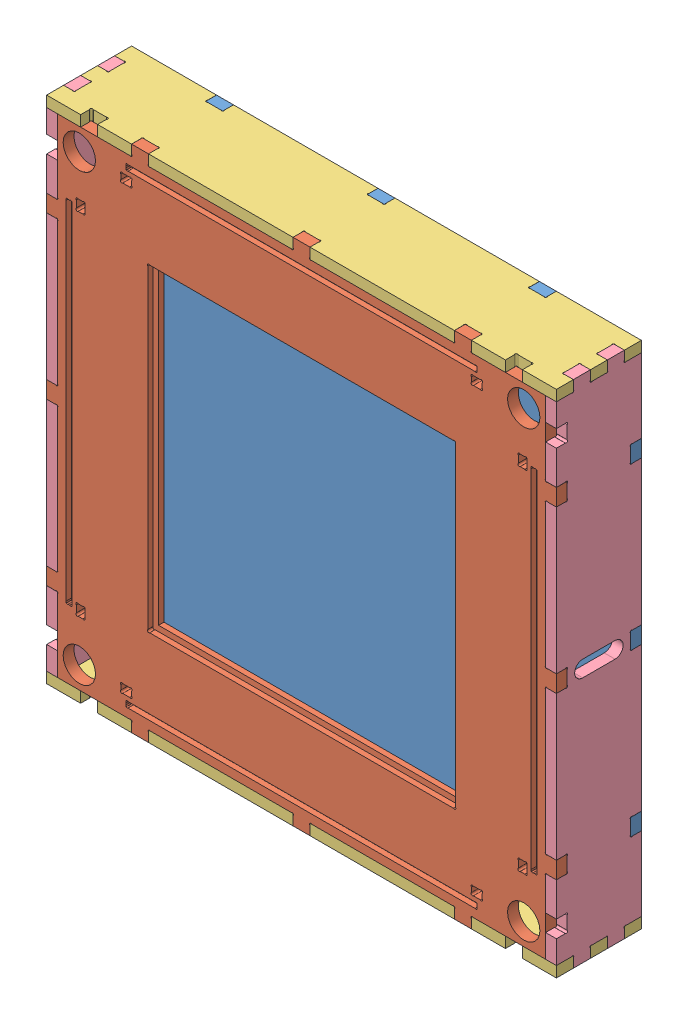
SolidWorks assembly res_assembly, configuration Default. Lengths in mm.
Overall size (300 300 50).
6 component instances, 4 part files, 15 mates.
Components (placement in the parent):
- pvc-025-res03-1: pvc-025-res03 [Default] at (-184.3986 -126.0576 6.3755) size (300 300 6.35)
- pvc-025-res01-1: pvc-025-res01 [Default] at (-184.3986 -126.0576 50.0255) size (300 300 6.35)
- pvc-250-res02-1: pvc-250-res02 [Default] at (102.9014 167.5924 56.3755) x (-1 0 0) z (0 -1 0) size (300 50 6.35)
- pvc-025-res04-1: pvc-025-res04 [a] at (-190.7486 161.2424 56.3755) x (0 -1 0) z (1 0 0) size (300 50 6.35)
- pvc-250-res02-5: pvc-250-res02 [Default] at (102.9014 -126.0576 56.3755) x (-1 0 0) z (0 -1 0) size (300 50 6.35)
- pvc-025-res04-2: pvc-025-res04 [b] at (109.2514 -126.0576 56.3755) x (0 1 0) z (-1 0 0) size (300 50 6.35)
Mates (geometry in assembly coordinates):
- Coincident1: coincident: plane of assembly; plane of assembly; plane of pvc-025-res01-1 through (103.4627 -82.9689 56.3755) normal (0 0 1); plane of pvc-250-res02-1 through (-130.7829 161.2424 56.3755) normal (0 0 1)
- Coincident2: coincident: plane of pvc-025-res01-1 through (-45.7486 167.5924 56.3755) normal (0 1 0); plane of pvc-250-res02-1 through (103.4627 167.5924 16.9368) normal (0 1 0)
- Coincident5: coincident: plane of pvc-025-res03-1 through (103.4627 -82.9689 6.3755) normal (0 0 -1); plane of pvc-250-res02-1 through (49.2171 161.2424 6.3755) normal (0 0 -1)
- Coincident6: coincident: plane of pvc-025-res03-1 through (-45.7486 167.5924 12.7255) normal (0 1 0); plane of pvc-250-res02-1 through (103.4627 167.5924 16.9368) normal (0 1 0)
- Coincident8: coincident: plane of pvc-025-res03-1 through (-184.3986 23.7149 12.7255) normal (-1 0 0); plane of pvc-025-res04-1 through (-184.3986 161.8036 15.8142) normal (1 0 0)
- Coincident9: coincident: plane of pvc-250-res02-1 through (103.4627 167.5924 16.9368) normal (0 1 0); plane of pvc-025-res04-1 through (-184.3986 167.5924 46.3755) normal (0 1 0)
- Coincident10: coincident: plane of pvc-250-res02-1 through (-190.7486 161.2424 56.3755) normal (0 0 1); plane of pvc-025-res04-1 through (-184.3986 147.5924 56.3755) normal (0 0 1)
- Coincident12: coincident: plane of pvc-250-res02-1 through (-190.7486 161.2424 46.3755) normal (-1 0 0); plane of pvc-025-res04-1 through (-190.7486 161.8036 15.8142) normal (-1 0 0)
- Coincident13: coincident: plane of pvc-025-res01-1 through (-190.7486 12.5924 56.3755) normal (-1 0 0); plane of pvc-025-res04-1 through (-190.7486 161.8036 15.8142) normal (-1 0 0)
- Coincident14: coincident: plane of assembly; plane of assembly; plane of pvc-025-res01-1 through (48.1289 -126.0576 56.3755) normal (0 -1 0); plane of pvc-250-res02-5 through (103.4627 -126.0576 16.9368) normal (0 1 0)
- Coincident15: coincident: plane of pvc-025-res01-1 through (109.2514 22.5924 56.3755) normal (1 0 0); plane of pvc-250-res02-5 through (109.2514 -132.4076 46.3755) normal (1 0 0)
- Coincident16: coincident: plane of pvc-025-res03-1 through (103.4627 -82.9689 6.3755) normal (0 0 -1); plane of pvc-250-res02-5 through (109.2514 -132.4076 6.3755) normal (0 0 -1)
- Coincident17: coincident: plane of pvc-250-res02-5 through (102.9014 -132.4076 37.498) normal (1 0 0); plane of pvc-025-res04-2 through (102.9014 -126.6189 15.8142) normal (-1 0 0)
- Coincident19: coincident: plane of pvc-025-res01-1 through (103.4627 -82.9689 56.3755) normal (0 0 1); plane of pvc-025-res04-2 through (102.9014 12.5924 56.3755) normal (0 0 1)
- Coincident20: coincident: plane of pvc-250-res02-5 through (103.4627 -132.4076 16.9368) normal (0 -1 0); plane of pvc-025-res04-2 through (102.9014 -132.4076 46.3755) normal (0 -1 0)
